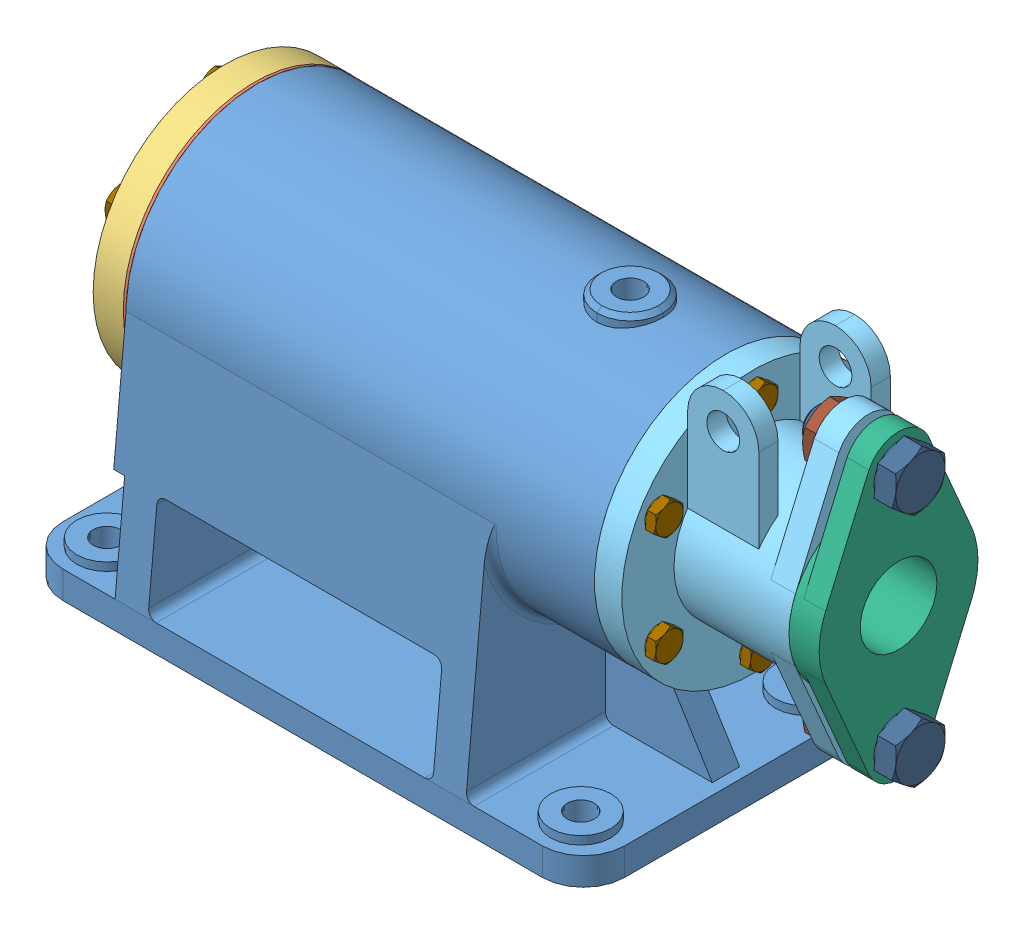
SolidWorks assembly Сборка корпуса - МЛИ2.01.00, configuration По умолчанию. Lengths in mm.
Overall size (271.95 155 112).
24 component instances, 11 part files, 51 mates.
Components (placement in the parent):
- Корпус - МЛИ2.00.01-1: Корпус - МЛИ2.00.01 [По умолчанию] at origin size (205 146 112)
- Прокладка - МЛИ2.00.07-1: Прокладка - МЛИ2.00.07 [По умолчанию] at (29 95 56) x (0 0 -1) z (1 0 0) size (96 96 1)
- Крышка - МЛИ2.00.02-3: Крышка - МЛИ2.00.02 [По умолчанию] at (18 95 56) x (0 0 -1) z (1 0 0) size (96 96 28)
- Кольцо уплотнительное-1: Кольцо уплотнительное [По умолчанию] at (35.9 95 56) x (-1 0 0) z (0 0.018689 0.999825) size (5.8 65.6 65.6)
- Стакан - МЛИ2.00.06-1: Стакан - МЛИ2.00.06 [По умолчанию] at (211 95 56) x (0 0 1) z (-1 0 0) size (96 115 56)
- Фланец - МЛИ2.00.03-2: Фланец - МЛИ2.00.03 [По умолчанию] at (222 95 56) x (0 0 -1) z (-1 0 0) size (58 110 44)
- Войлок-1: Войлок [По умолчанию] at (222 95 56) x (-1 0 0) z (0 -0.983768 0.179447) size (27 45 45)
- Кольцо уплотнительное 1-1: Кольцо уплотнительное 1 [По умолчанию] at (182.9 95 56) size (5.8 33.8 33.8)
- hex screw gradeab_iso_var1-14: hex screw gradeab_iso_var1 [ISO 4017 - M6 x 25-N] at (14 135 56) size (29 11.55 10)
- hex screw gradeab_iso_var1-15: hex screw gradeab_iso_var1 [ISO 4017 - M6 x 25-N] at (14 115 90.641) size (29 11.55 10)
- hex screw gradeab_iso_var1-16: hex screw gradeab_iso_var1 [ISO 4017 - M6 x 25-N] at (14 75 90.641) size (29 11.55 10)
- hex screw gradeab_iso_var1-17: hex screw gradeab_iso_var1 [ISO 4017 - M6 x 25-N] at (14 55 56) size (29 11.55 10)
- hex screw gradeab_iso_var1-18: hex screw gradeab_iso_var1 [ISO 4017 - M6 x 25-N] at (14 75 21.359) size (29 11.55 10)
- hex screw gradeab_iso_var1-19: hex screw gradeab_iso_var1 [ISO 4017 - M6 x 25-N] at (14 115 21.359) size (29 11.55 10)
- hex screw gradeab_iso_var1-22: hex screw gradeab_iso_var1 [ISO 4017 - M6 x 25-N] at (215 115 90.641) x (-1 0 0) z (0 0.924225 0.381849) size (29 11.55 10)
- hex screw gradeab_iso_var1-23: hex screw gradeab_iso_var1 [ISO 4017 - M6 x 25-N] at (215 75 90.641) x (-1 0 0) z (0 0.924225 0.381849) size (29 11.55 10)
- hex screw gradeab_iso_var1-24: hex screw gradeab_iso_var1 [ISO 4017 - M6 x 25-N] at (215 55 56) x (-1 0 0) z (0 0.924225 0.381849) size (29 11.55 10)
- hex screw gradeab_iso_var1-25: hex screw gradeab_iso_var1 [ISO 4017 - M6 x 25-N] at (215 75 21.359) x (-1 0 0) z (0 0.924225 0.381849) size (29 11.55 10)
- hex screw gradeab_iso_var1-26: hex screw gradeab_iso_var1 [ISO 4017 - M6 x 25-N] at (215 115 21.359) x (-1 0 0) z (0 0.924225 0.381849) size (29 11.55 10)
- hex screw gradeab_iso_var1-27: hex screw gradeab_iso_var1 [ISO 4017 - M6 x 25-N] at (215 135 56) x (-1 0 0) z (0 0.924225 0.381849) size (29 11.55 10)
- hex screw gradec_iso_var1-4: hex screw gradec_iso_var1 [ISO 4018 - M12 x 30-WN] at (271.95 52 56) x (-1 0 0) z (0 0.924225 0.381849) size (37.95 20.78 18)
- hex screw gradec_iso_var1-5: hex screw gradec_iso_var1 [ISO 4018 - M12 x 30-WN] at (271.95 138 56) x (-1 0 0) z (0 0.924225 0.381849) size (37.95 20.78 18)
- hex thin nut chamfered gradeab_iso_var1-4: hex thin nut chamfered gradeab_iso_var1 [ISO - 4035 - M12 - N] at (238 52 56) x (0 0 1) z (-1 0 0) size (18 20.78 6)
- hex thin nut chamfered gradeab_iso_var1-5: hex thin nut chamfered gradeab_iso_var1 [ISO - 4035 - M12 - N] at (238 138 56) x (0 0 1) z (-1 0 0) size (18 20.78 6)
Mates (geometry in assembly coordinates):
- Совпадение1: coincident anti-aligned: plane of Корпус - МЛИ2.00.01-1 through (30 0 0) normal (-1 0 0); plane of Прокладка - МЛИ2.00.07-1 through (30 95 56) normal (1 0 0)
- Концентричный3: concentric anti-aligned: cylinder of Крышка - МЛИ2.00.02-3 through (46 95 56) axis (-1 0 0) radius 33; axis of Кольцо уплотнительное-1 through (17.3093 95 56) axis (1 0 0)
- Касательность3: tangent anti-aligned: plane of Крышка - МЛИ2.00.02-3 through (33 95 56) normal (1 0 0); torus of Кольцо уплотнительное-1
- Параллельность1: parallel anti-aligned: plane of Прокладка - МЛИ2.00.07-1 through (29 95 56) normal (-1 0 0); plane of Крышка - МЛИ2.00.02-3 through (29 95 56) normal (1 0 0)
- Граничное расстояние1: limit distance = 0 mm anti-aligned: plane of Крышка - МЛИ2.00.02-3 through (29 95 56) normal (1 0 0); plane of Прокладка - МЛИ2.00.07-1 through (29 95 56) normal (-1 0 0)
- Совпадение2: coincident anti-aligned: plane of Корпус - МЛИ2.00.01-1 through (201 0 0) normal (1 0 0); plane of Стакан - МЛИ2.00.06-1 through (201 95 56) normal (-1 0 0)
- Граничное расстояние3: limit distance = 0 mm anti-aligned: plane of Фланец - МЛИ2.00.03-2 through (253 95 56) normal (-1 0 0); plane of Стакан - МЛИ2.00.06-1 through (253 52 56) normal (1 0 0)
- Концентричный14: concentric aligned: cylinder of Стакан - МЛИ2.00.06-1 through (244 138 56) axis (1 0 0) radius 6; cylinder of Фланец - МЛИ2.00.03-2 through (255 138 56) axis (1 0 0) radius 6
- Концентричный15: concentric aligned: cylinder of Стакан - МЛИ2.00.06-1 through (197 95 56) axis (1 0 0) radius 22.5; cylinder of Войлок-1 through (222 95 56) axis (1 0 0) radius 22.5
- Совпадение8: coincident anti-aligned: line of Корпус - МЛИ2.00.01-1 through (165 95 56) axis (1 0 0); line of Кольцо уплотнительное 1-1 through (192.5302 95 56) axis (-1 0 0)
- Касательность5: tangent anti-aligned: plane of Корпус - МЛИ2.00.01-1 through (180 95 56) normal (1 0 0); torus of Кольцо уплотнительное 1-1
- Концентричный161: concentric aligned: cylinder of Крышка - МЛИ2.00.02-3 through (29 135 56) axis (-1 0 0) radius 3; cylinder of hex screw gradeab_iso_var1-14 through (14 135 56) axis (-1 0 0) radius 5
- Совпадение91: coincident anti-aligned: plane of Крышка - МЛИ2.00.02-3 through (18 95 56) normal (-1 0 0); plane of hex screw gradeab_iso_var1-14 through (18 140.7735 56) normal (1 0 0)
- Концентричный171: concentric aligned: cylinder of Крышка - МЛИ2.00.02-3 through (29 115 90.641) axis (-1 0 0) radius 3; cylinder of hex screw gradeab_iso_var1-15 through (14 115 90.641) axis (-1 0 0) radius 5
- Совпадение101: coincident anti-aligned: plane of Крышка - МЛИ2.00.02-3 through (18 95 56) normal (-1 0 0); plane of hex screw gradeab_iso_var1-15 through (18 120.7735 90.641) normal (1 0 0)
- Концентричный181: concentric aligned: cylinder of Крышка - МЛИ2.00.02-3 through (29 75 90.641) axis (-1 0 0) radius 3; cylinder of hex screw gradeab_iso_var1-16 through (14 75 90.641) axis (-1 0 0) radius 5
- Совпадение111: coincident anti-aligned: plane of Крышка - МЛИ2.00.02-3 through (18 95 56) normal (-1 0 0); plane of hex screw gradeab_iso_var1-16 through (18 80.7735 90.641) normal (1 0 0)
- Концентричный191: concentric aligned: cylinder of Крышка - МЛИ2.00.02-3 through (29 55 56) axis (-1 0 0) radius 3; cylinder of hex screw gradeab_iso_var1-17 through (14 55 56) axis (-1 0 0) radius 5
- Совпадение121: coincident anti-aligned: plane of Крышка - МЛИ2.00.02-3 through (18 95 56) normal (-1 0 0); plane of hex screw gradeab_iso_var1-17 through (18 60.7735 56) normal (1 0 0)
- Концентричный201: concentric aligned: cylinder of Крышка - МЛИ2.00.02-3 through (29 75 21.359) axis (-1 0 0) radius 3; cylinder of hex screw gradeab_iso_var1-18 through (14 75 21.359) axis (-1 0 0) radius 5
- Совпадение131: coincident anti-aligned: plane of Крышка - МЛИ2.00.02-3 through (18 95 56) normal (-1 0 0); plane of hex screw gradeab_iso_var1-18 through (18 80.7735 21.359) normal (1 0 0)
- Концентричный211: concentric aligned: cylinder of Крышка - МЛИ2.00.02-3 through (29 115 21.359) axis (-1 0 0) radius 3; cylinder of hex screw gradeab_iso_var1-19 through (14 115 21.359) axis (-1 0 0) radius 5
- Совпадение141: coincident anti-aligned: plane of Крышка - МЛИ2.00.02-3 through (18 95 56) normal (-1 0 0); plane of hex screw gradeab_iso_var1-19 through (18 120.7735 21.359) normal (1 0 0)
- Концентричный231: concentric anti-aligned: cylinder of Стакан - МЛИ2.00.06-1 through (211 115 90.641) axis (-1 0 0) radius 3; cylinder of hex screw gradeab_iso_var1-22 through (215 115 90.641) axis (1 0 0) radius 5
- Совпадение161: coincident anti-aligned: plane of Стакан - МЛИ2.00.06-1 through (211 95 56) normal (1 0 0); plane of hex screw gradeab_iso_var1-22 through (211 112.7954 95.977) normal (-1 0 0)
- Концентричный241: concentric anti-aligned: cylinder of Стакан - МЛИ2.00.06-1 through (211 75 90.641) axis (-1 0 0) radius 3; cylinder of hex screw gradeab_iso_var1-23 through (215 75 90.641) axis (1 0 0) radius 5
- Совпадение171: coincident anti-aligned: plane of Стакан - МЛИ2.00.06-1 through (211 95 56) normal (1 0 0); plane of hex screw gradeab_iso_var1-23 through (211 72.7954 95.977) normal (-1 0 0)
- Концентричный251: concentric anti-aligned: cylinder of Стакан - МЛИ2.00.06-1 through (211 55 56) axis (-1 0 0) radius 3; cylinder of hex screw gradeab_iso_var1-24 through (215 55 56) axis (1 0 0) radius 5
- Совпадение181: coincident anti-aligned: plane of Стакан - МЛИ2.00.06-1 through (211 95 56) normal (1 0 0); plane of hex screw gradeab_iso_var1-24 through (211 52.7954 61.336) normal (-1 0 0)
- Концентричный261: concentric anti-aligned: cylinder of Стакан - МЛИ2.00.06-1 through (211 75 21.359) axis (-1 0 0) radius 3; cylinder of hex screw gradeab_iso_var1-25 through (215 75 21.359) axis (1 0 0) radius 5
- Совпадение191: coincident anti-aligned: plane of Стакан - МЛИ2.00.06-1 through (211 95 56) normal (1 0 0); plane of hex screw gradeab_iso_var1-25 through (211 72.7954 26.695) normal (-1 0 0)
- Концентричный271: concentric anti-aligned: cylinder of Стакан - МЛИ2.00.06-1 through (211 115 21.359) axis (-1 0 0) radius 3; cylinder of hex screw gradeab_iso_var1-26 through (215 115 21.359) axis (1 0 0) radius 5
- Совпадение201: coincident anti-aligned: plane of Стакан - МЛИ2.00.06-1 through (211 95 56) normal (1 0 0); plane of hex screw gradeab_iso_var1-26 through (211 112.7954 26.695) normal (-1 0 0)
- Концентричный281: concentric anti-aligned: cylinder of Стакан - МЛИ2.00.06-1 through (211 135 56) axis (-1 0 0) radius 3; cylinder of hex screw gradeab_iso_var1-27 through (215 135 56) axis (1 0 0) radius 5
- Совпадение211: coincident anti-aligned: plane of Стакан - МЛИ2.00.06-1 through (211 95 56) normal (1 0 0); plane of hex screw gradeab_iso_var1-27 through (211 132.7954 61.336) normal (-1 0 0)
- Концентричный291: concentric aligned: cylinder of Фланец - МЛИ2.00.03-2 through (255 52 56) axis (1 0 0) radius 6; cylinder of hex screw gradec_iso_var1-4 through (271.95 52 56) axis (1 0 0) radius 6
- Совпадение221: coincident anti-aligned: plane of Фланец - МЛИ2.00.03-2 through (264 138 56) normal (1 0 0); plane of hex screw gradec_iso_var1-4 through (264 35.364 49.1267) normal (-1 0 0)
- Концентричный301: concentric aligned: cylinder of Фланец - МЛИ2.00.03-2 through (255 138 56) axis (1 0 0) radius 6; cylinder of hex screw gradec_iso_var1-5 through (271.95 138 56) axis (1 0 0) radius 6
- Совпадение231: coincident anti-aligned: plane of Фланец - МЛИ2.00.03-2 through (264 138 56) normal (1 0 0); plane of hex screw gradec_iso_var1-5 through (264 121.364 49.1267) normal (-1 0 0)
- Концентричный31: concentric anti-aligned: cylinder of hex screw gradec_iso_var1-4 through (271.95 52 56) axis (1 0 0) radius 6; cylinder of hex thin nut chamfered gradeab_iso_var1-4 through (263.0375 52 56) axis (-1 0 0) radius 6
- Совпадение24: coincident anti-aligned: plane of Стакан - МЛИ2.00.06-1 through (244 52 56) normal (-1 0 0); plane of hex thin nut chamfered gradeab_iso_var1-4 through (244 62.3923 56) normal (1 0 0)
- Концентричный32: concentric anti-aligned: cylinder of hex screw gradec_iso_var1-5 through (271.95 138 56) axis (1 0 0) radius 6; cylinder of hex thin nut chamfered gradeab_iso_var1-5 through (263.0375 138 56) axis (-1 0 0) radius 6
- Совпадение25: coincident anti-aligned: plane of Стакан - МЛИ2.00.06-1 through (244 52 56) normal (-1 0 0); plane of hex thin nut chamfered gradeab_iso_var1-5 through (244 148.3923 56) normal (1 0 0)
- Концентричный302: concentric aligned: cylinder of Корпус - МЛИ2.00.01-1 through (30 135 56) axis (-1 0 0) radius 2.5; cylinder of hex screw gradeab_iso_var1-14 through (14 135 56) axis (-1 0 0) radius 3
- Концентричный303: concentric aligned: cylinder of Корпус - МЛИ2.00.01-1 through (30 115 21.359) axis (-1 0 0) radius 2.5; cylinder of hex screw gradeab_iso_var1-19 through (14 115 21.359) axis (-1 0 0) radius 3
- Совпадение232: coincident anti-aligned: plane of Прокладка - МЛИ2.00.07-1 through (29 95 56) normal (-1 0 0); plane of Крышка - МЛИ2.00.02-3 through (29 95 56) normal (1 0 0)
- Концентричный305: concentric aligned: cylinder of Корпус - МЛИ2.00.01-1 through (201 115 21.359) axis (1 0 0) radius 2.5; cylinder of hex screw gradeab_iso_var1-26 through (215 115 21.359) axis (1 0 0) radius 3
- Концентричный306: concentric aligned: circle of Корпус - МЛИ2.00.01-1; cylinder of hex screw gradeab_iso_var1-23 through (215 75 90.641) axis (1 0 0) radius 3
- Концентричный307: concentric aligned: cylinder of Стакан - МЛИ2.00.06-1 through (197 95 56) axis (1 0 0) radius 22.5; cylinder of Фланец - МЛИ2.00.03-2 through (220 95 56) axis (1 0 0) radius 22.5
- Совпадение239: coincident anti-aligned: plane of Стакан - МЛИ2.00.06-1 through (253 52 56) normal (1 0 0); plane of Фланец - МЛИ2.00.03-2 through (253 95 56) normal (-1 0 0)
- Совпадение240: coincident anti-aligned: plane of Корпус - МЛИ2.00.01-1 through (195 95 56) normal (1 0 0); plane of Войлок-1 through (195 92.4877 42.2273) normal (-1 0 0)
